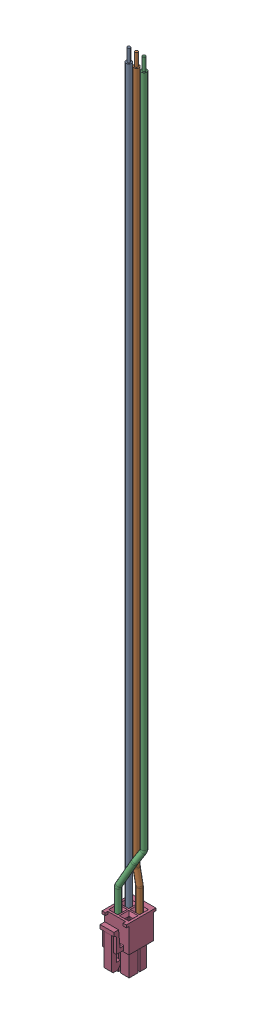
SolidWorks assembly 1393835_ASM, configuration Default. Lengths in mm.
Overall size (9.68 311 14.4).
2 component instances, 2 part files, 0 mates.
Components (placement in the parent):
- 1393837-1: 1393837 [Default] at origin size (8.17 293.4 6.4)
- 1393836-1: 1393836 [Default] at (-2.33 -79.7 -1) x (1 0 0) z (0 -1 0) size (9.6 14.4 19.6)
